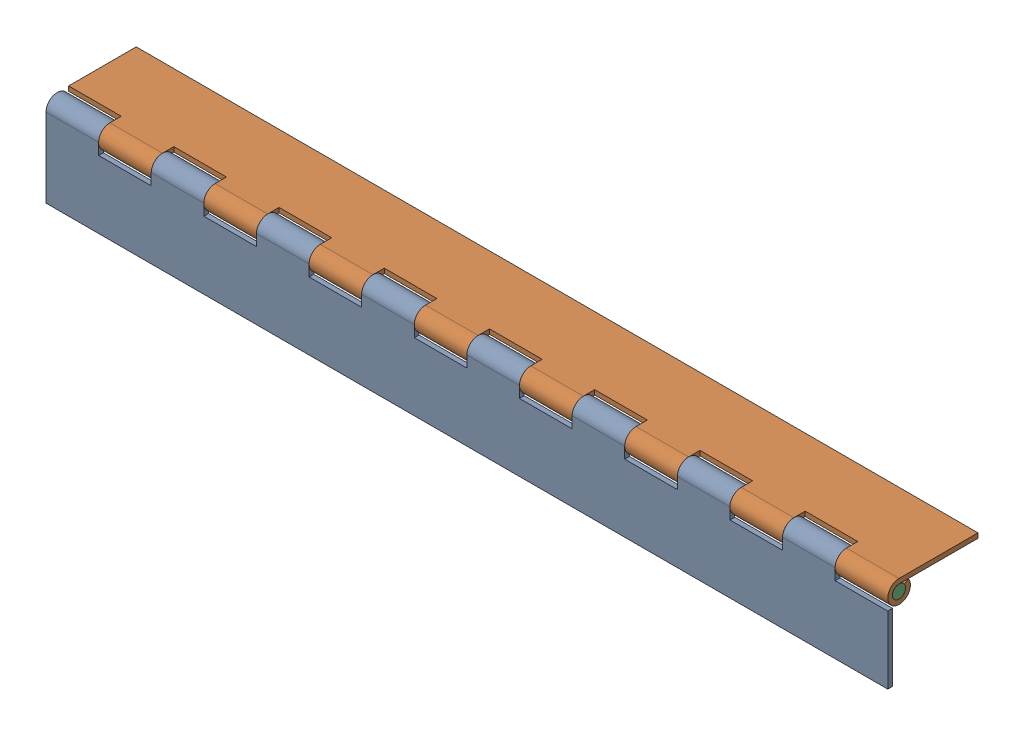
SolidWorks assembly FE-00004-02_ASM, configuration Default. Lengths in mm.
Overall size (406.4 43.56 43.56).
3 component instances, 2 part files, 0 mates.
Components (placement in the parent):
- FE-00004-02-A-1: FE-00004-02-A [Default] at origin size (406.4 43.56 10.92)
- FE-00004-02-A-2: FE-00004-02-A [Default] at (0 5.461 -5.461) x (-1 0 0) z (0 1 0) size (406.4 43.56 10.92)
- FE-00004-02-B-1: FE-00004-02-B [Default] at (0 0 -5.461) size (406.4 6.35 6.35)
